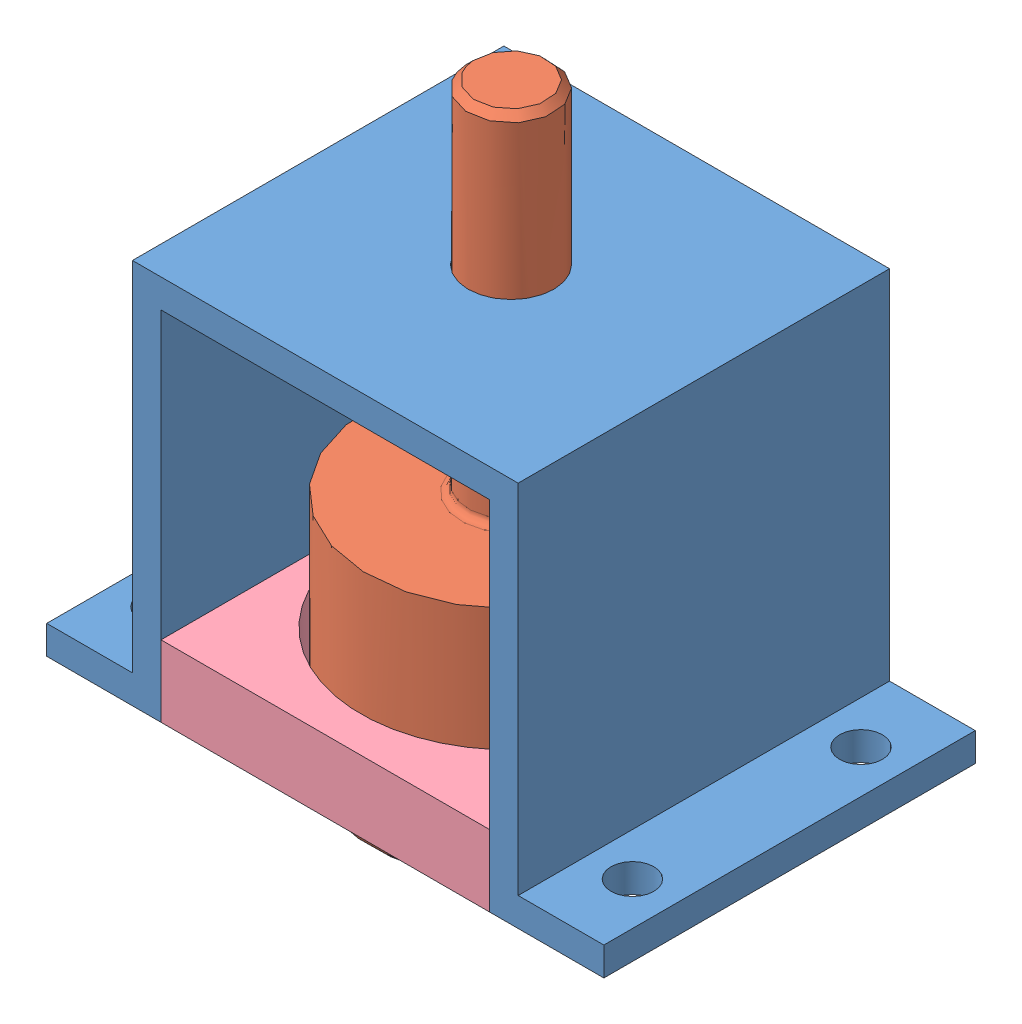
SolidWorks assembly fixation bille, configuration Défaut. Lengths in mm.
Overall size (39 47.17 26).
5 component instances, 4 part files, 4 mates.
Components (placement in the parent):
- Fixation bille-1: Fixation bille [Défaut] at (-20.545 -7.9974 0) size (39 27 26)
- Roulette à bille 687-679-1: Roulette à bille 687-679 [Default] at (-3.7752 -6.3161 13.5736) x (0.301673 0 0.953411) z (-0.953411 0 0.301673) size (20 47.17 20)
  - Roulette D20-1: Roulette D20 [Default] at (-2.1367 -5.4811 4.8512) size (20 42 20)
  - bille D12_5-1: bille D12_5 [Default] at (-2.1367 -2.2311 4.8512) x (0.951271 -0.300034 -0.071154) z (0.043636 -0.097448 0.994284) size (12.5 12.5 12.5)
- Guide_roulette-1: Guide_roulette [Défaut] at (2.455 -7.9974 0) x (-1 0 0) z (0 0 -1) size (23 8 26)
Mates (geometry in assembly coordinates):
- Coaxiale1: concentric anti-aligned: cylinder of Fixation bille-1; cylinder of Roulette à bille 687-679-1/Roulette D20-1
- Coïncidente5: coincident anti-aligned: plane of Fixation bille-1 through (2.455 17.0026 26) normal (-1 0 0); plane of Guide_roulette-1 through (0 2.455 0.0026) normal (0 1 0)
- Coïncidente6: coincident aligned: plane of Fixation bille-1 through (-28.545 -5.9974 26) normal (0 0 1); plane of Guide_roulette-1 through (2.455 0.0026 26) normal (0 0 1)
- Coïncidente9: coincident aligned: unknown of Fixation bille-1; unknown of Guide_roulette-1
